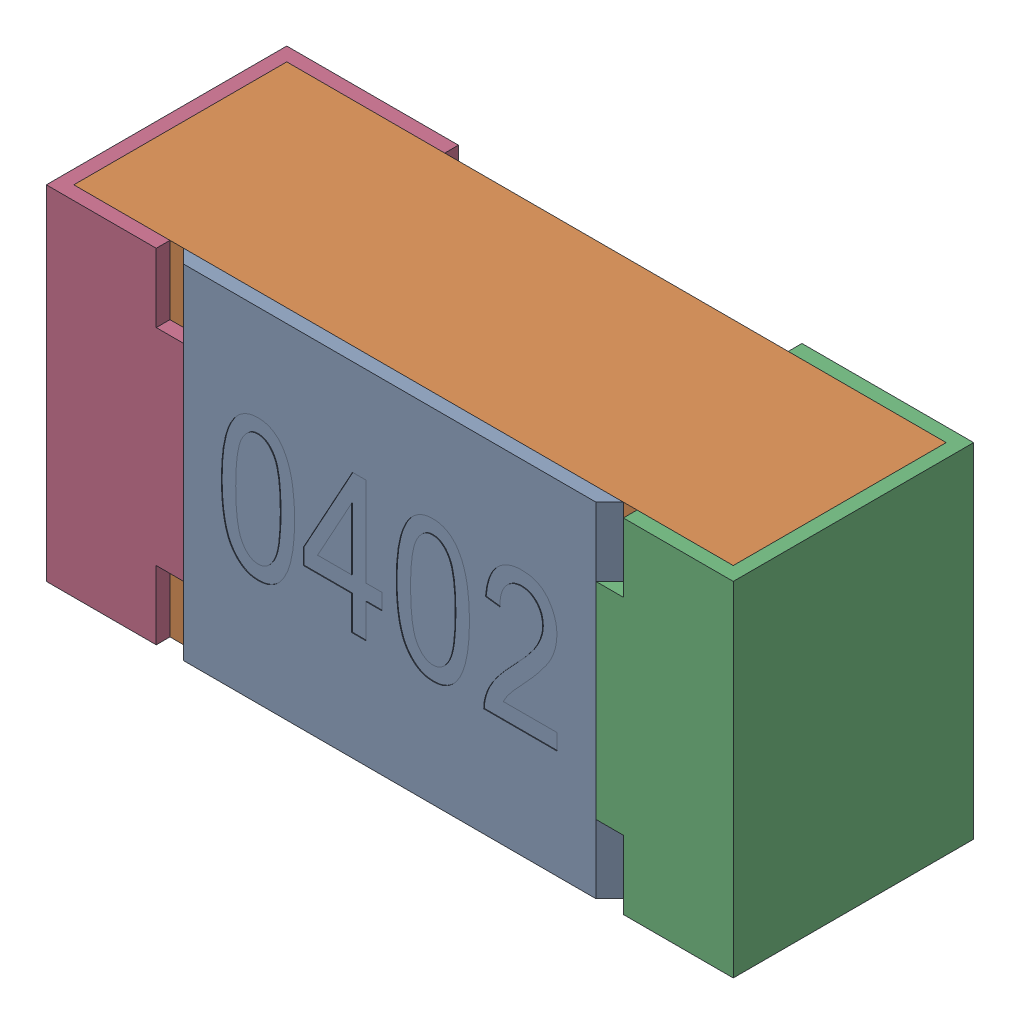
SolidWorks assembly R2, configuration Standard. Lengths in mm.
Overall size (1 0.5 0.35).
5 component instances, 4 part files, 0 mates.
Components (placement in the parent):
- R2-subassembly-1-1: R2-subassembly-1 [Standard] at (3.3001 12.7 0) size (1 0.5 0.35)
  - User Library-R_0402-1: User Library-R_0402 [Standard] at origin size (0.64 0.5 0.02)
  - User Library-R_0402-1-1: User Library-R_0402-1 [Standard] at origin size (0.96 0.5 0.31)
  - User Library-R_0402-2-1: User Library-R_0402-2 [Standard] at origin size (0.25 0.5 0.35)
  - User Library-R_0402-3-1: User Library-R_0402-3 [Standard] at origin size (0.25 0.5 0.35)
